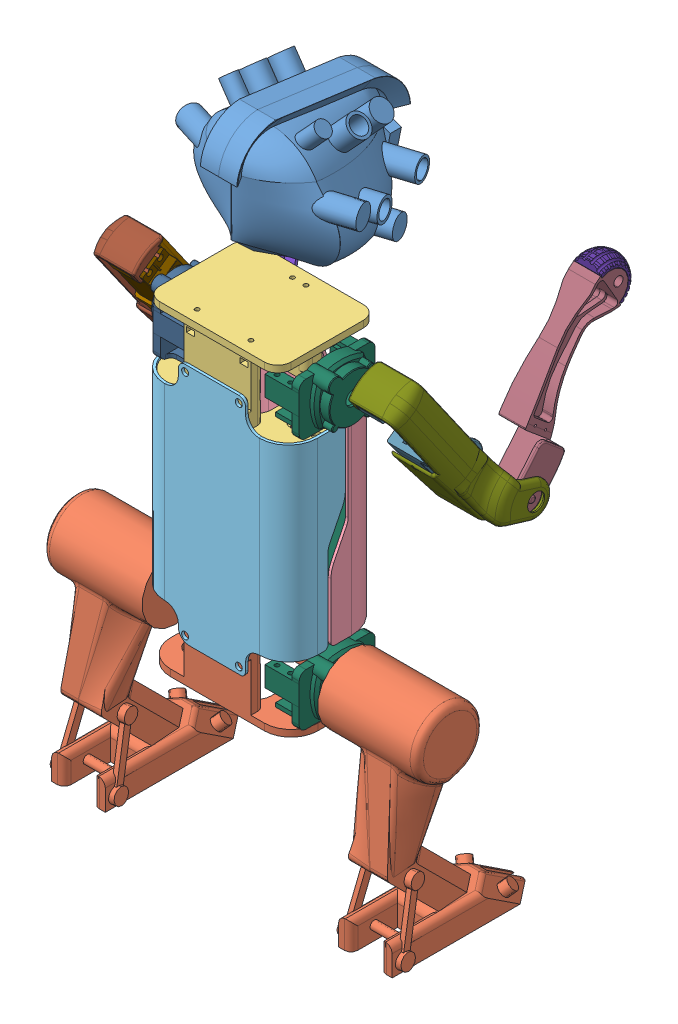
SolidWorks assembly SpotMicroAI, configuration 00. Lengths in mm.
Overall size (344.81 486.01 235.57).
36 component instances, 24 part files, 20 mates.
Components (placement in the parent):
- Rear_Shoulder-1: Rear_Shoulder [Default] at origin size (110 57.5 70)
  - Rear_Inner_Shoulder-1: Rear_Inner_Shoulder [Default] at (267.0968 85.9341 878.7869) x (-1 0 0) z (0 0 -1) size (110 5.15 70)
  - Rear_Outer_Shoulder-1: Rear_Outer_Shoulder [Default] at (267.0969 90.6943 -58.2152) x (-1 0 0) z (0 0 1) size (110 52.53 70)
- Front Shoulder-1: Front Shoulder [Default] at origin size (110 52.5 70)
  - Front_Inner_Shoulder-1: Front_Inner_Shoulder [Default] at (115.6208 217.934 444.7666) x (-1 0 0) z (0 1 0) size (110 70 52.5)
- Covers-1: Covers [Default] at origin size (115.6 323.29 74)
  - Cover_Nose-1: Cover_Nose [Default] at (291.792 648.6711 914.4489) x (0 1 0) z (0 0 -1) size (93.46 115.6 70.05) (hidden)
  - Cover_Bottom-1: Cover_Bottom [Default] at (1154.1394 1170.0941 1665.8069) x (0 -1 0) z (-1 0 0) size (180 42.4 114)
  - Cover_Top-1: Cover_Top [Default] at (1154.1394 -861.2249 -846.2737) x (0 1 0) z (-1 0 0) size (180 42.5 114.01)
  - Cover_Rear_Plain-1: Cover_Rear_Plain [Default] at (398.4845 261.595 791.8833) x (0 0 -1) z (0 1 0) size (70.05 114.01 69.83) (hidden)
- Chassis-1: Chassis [Default] at origin size (110 127 29)
  - Chassis_Right_Side-1: Chassis_Right_Side [Default] at (205.6209 154.434 412.2666) x (0 0 1) z (-1 0 0) size (29 127 6.5)
  - Chassis_Left_Side-1: Chassis_Left_Side [Default] at (95.6208 154.4341 412.2666) x (0 0 1) z (1 0 0) size (29 127 6.5)
- Left Arm-1: Left Arm [Default] at (15.3219 0 395.1883) x (0 1 0) z (0.258819 0 -0.965926) size (144.09 143.1 205.53)
  - Left_Wrist-1: Left_Wrist [Default] at (208.18 556.7001 -69.0557) x (0.766044 -0.166366 0.620885) z (-0.642788 -0.198267 0.739942) size (150.01 36.9 30.01)
  - Left_MidLimb-1: Left_MidLimb [Default] at (818.6858 196.1975 -412.3318) x (-0.573576 0.212012 -0.79124) z (-0.819152 -0.148453 0.554032) size (40.2 40.42 137.43)
  - Left_Hind_Limb-1: Left_Hind_Limb [Default] at (269.686 62.3829 30.3404) x (0 -0.965926 -0.258819) z (0 0.258819 -0.965926) size (37.51 46 56.55)
  - Left_MidLimb_Cover-1: Left_MidLimb_Cover [Default] at (1075.7599 185.3339 -217.1444) x (-0.573576 0.212012 -0.79124) z (-0.819152 -0.148453 0.554032) size (43.12 46.4 143.61)
  - Foot-1: Foot [Default] at (334.478 189.9471 78.7023) x (0.864275 0.130191 -0.48588) z (-0.50302 0.223691 -0.834825) size (39.57 20.99 19.53)
- Left Arm_1-1: Left Arm_1 [Default] at (15.3219 -285 395.1883) x (0 1 0) z (0.258819 0 -0.965926) size (46 50.87 64.33)
  - Left_Hind_Limb-1: Left_Hind_Limb [Default] at (367.1861 62.3831 30.3403) x (0 -0.965926 -0.258819) z (0 0.258819 -0.965926) size (37.51 46 56.55) (hidden)
- Right Arm(Mirror)-1: Right Arm(Mirror) [Default] at (285.9198 0 395.1883) x (0 1 0) z (0.258819 0 0.965926) size (144.09 143.1 205.53)
  - Right_Wrist-1: Right_Wrist [Default] at (208.18 556.7001 69.0557) x (0.766044 -0.166366 -0.620885) z (0.642788 0.198267 0.739942) size (150.01 36.9 30.01)
  - Right_MidLimb-1: Right_MidLimb [Default] at (818.6858 196.1975 412.3318) x (-0.573576 0.212012 0.79124) z (0.819152 0.148453 0.554032) size (40.2 40.42 137.43)
  - Right_Hind_Limb-1: Right_Hind_Limb [Default] at (269.686 62.3829 -30.3404) x (0 -0.965926 0.258819) z (0 -0.258819 -0.965926) size (37.61 46 56.55)
  - Right_MidLimb_Cover-1: Right_MidLimb_Cover [Default] at (1075.7599 185.3339 217.1444) x (-0.573576 0.212012 0.79124) z (0.819152 0.148453 0.554032) size (43.12 46.48 143.61)
  - Foot(Mirror)-1: Foot(Mirror) [Default] at (334.478 189.9471 -78.7023) x (0.864275 0.130191 0.48588) z (0.50302 -0.223691 -0.834825) size (39.57 20.99 19.53)
- Right Arm(Mirror)_1-1: Right Arm(Mirror)_1 [Default] at (285.9198 -285 395.1883) x (0 1 0) z (0.258819 0 0.965926) size (46 50.96 64.36)
  - Right_Hind_Limb-1: Right_Hind_Limb [Default] at (367.1861 62.3831 -30.3403) x (0 -0.965926 0.258819) z (0 -0.258819 -0.965926) size (37.61 46 56.55)
- Servo Motor MG996R  With Attachments-2: Servo Motor MG996R  With Attachments [По умолчанию] at (64.3664 178.4471 324.2238) x (0 -0.76661 0.642114) z (0 0.642114 0.76661) size (56.95 44.55 19.7)
- Servo Motor MG996R  With Attachments-4: Servo Motor MG996R  With Attachments [По умолчанию] at (71.1148 242.1871 397.9446) x (0 0.819152 0.573576) z (0 0.573576 -0.819152) size (56.95 44.55 19.7)
- Голова-1: Голова [По умолчанию] at (150.6209 312.2493 326.128) size (134.3 100.82 129.63)
- Бёдрышко-1: Бёдрышко [Правая] at (257.4935 -81.8487 439.3311) x (0 0 1) z (0 -1 0) size (113.52 74 166.38)
- Бёдрышко-5: Бёдрышко [Левая] at (126.7482 -81.8487 439.3311) x (0 0 1) z (0 -1 0) size (113.52 74 166.38)
- Деталь2^SpotMicroAI-1: Деталь2^SpotMicroAI [По умолчанию] at origin (virtual)
- Верхушка-Власти-1: Верхушка-Власти [По умолчанию] at (150.6209 275.434 409.7667) x (1 0 0) z (0 -1 0) size (98 74 5)
Mates (geometry in assembly coordinates):
- Совпадение3: coincident anti-aligned: plane of Left Arm-1/Left_Wrist-1 through (64.3664 259.7717 255.9142) normal (1 0 0); plane of Servo Motor MG996R  With Attachments-2 through (64.3664 194.7722 302.0383) normal (-1 0 0)
- Концентричный14: concentric aligned: circle of Left Arm-1/Left_Wrist-1; cylinder of Servo Motor MG996R  With Attachments-2 through (66.7664 200.5533 312.1319) axis (-1 0 0) radius 2.1
- Параллельность4: parallel aligned: cylinder of Left Arm-1/Left_Wrist-1 through (64.3664 194.125 304.4711) axis (-1 0 0) radius 1.5; cylinder of Servo Motor MG996R  With Attachments-2 through (66.7664 194.2285 304.5808) axis (-1 0 0) radius 2.1
- Совпадение5: coincident anti-aligned: plane of Left Arm-1/Left_MidLimb-1 through (71.1148 192.4364 373.9508) normal (1 0 0); plane of Servo Motor MG996R  With Attachments-4 through (71.1148 216.5235 387.9404) normal (-1 0 0)
- Концентричный16: concentric aligned: cylinder of Left Arm-1/Left_MidLimb_Cover-1 through (70.9148 259.6044 416.1527) axis (-1 0 0) radius 2.0995; cylinder of Servo Motor MG996R  With Attachments-4 through (73.5148 259.6044 416.1527) axis (-1 0 0) radius 2.1
- Параллельность7: parallel: line of Left Arm-1/Left_MidLimb-1 through (71.1148 272.6314 404.522) axis (0 -0.819152 -0.573576); plane of Servo Motor MG996R  With Attachments-4 through (73.5148 225.7197 374.3894) normal (0 0.573576 -0.819152)
- Совпадение9: coincident anti-aligned: plane of Covers-1/Cover_Top-1 through (115.1208 224.434 446.7666) normal (0 0 1); plane of koltuk-2 through (154.166 214.1134 446.7666) normal (0 0 -1)
- Параллельность8: parallel anti-aligned: line of Covers-1/Cover_Nose-1 through (185.6209 278.8949 444.7666) axis (-1 0 0); line of koltuk-2 through (122.0356 220.6675 462.9431) axis (1 0 0)
- Совпадение10: coincident: point of Covers-1/Cover_Nose-1; unknown of Голова-1
- Параллельность9: parallel anti-aligned: plane of Covers-1/Cover_Bottom-1 through (207.6208 84.4352 399.7666) normal (1 0 0); plane of Бёдрышко-1 through (215.9935 59.6732 408.6366) normal (-1 0 0)
- Параллельность10: parallel aligned: plane of Rear_Shoulder-1/Rear_Outer_Shoulder-1 through (111.6209 33.4341 418.7665) normal (0 -1 0); plane of Бёдрышко-1 through (277.4935 -81.8487 439.3311) normal (0 -1 0)
- Параллельность13: parallel anti-aligned: plane of Covers-1/Cover_Top-1 through (93.6208 224.434 404.2666) normal (-1 0 0); plane of Бёдрышко-2 through (130.25 0.5275 310.0801) normal (1 0 0)
- Параллельность14: parallel aligned: plane of Rear_Shoulder-1/Rear_Outer_Shoulder-1 through (111.6209 33.4341 418.7665) normal (0 -1 0); plane of Бёдрышко-2 through (68.75 -140.9945 279.3855) normal (0 -1 0)
- Параллельность15: parallel anti-aligned: plane of Covers-1/Cover_Top-1 through (93.6208 224.434 404.2666) normal (-1 0 0); plane of Бёдрышко-5 through (85.2482 59.6732 408.6366) normal (1 0 0)
- Параллельность16: parallel aligned: plane of Rear_Shoulder-1/Rear_Outer_Shoulder-1 through (111.6209 33.4341 418.7665) normal (0 -1 0); plane of Бёдрышко-5 through (23.7482 -81.8487 439.3311) normal (0 -1 0)
- Концентричный17: concentric anti-aligned: cylinder of Бёдрышко-1 through (289.9935 59.6732 408.6366) axis (-1 0 0) radius 24.8578; cylinder of Бёдрышко-5 through (11.2482 59.6732 408.6366) axis (1 0 0) radius 24.8578
- Симметричный1: symmetric aligned: plane of Бёдрышко-1 through (215.9935 59.6732 408.6366) normal (-1 0 0); plane of Бёдрышко-5 through (85.2482 59.6732 408.6366) normal (1 0 0)
- Совпадение24: coincident anti-aligned: plane of Front Shoulder-1/Front_Inner_Shoulder-1 through (150.6208 270.434 380.7666) normal (0 1 0); plane of Верхушка-Власти-1 through (111.6209 270.434 382.7667) normal (0 -1 0)
- Концентричный18: concentric aligned: cylinder of Front Shoulder-1/Front_Inner_Shoulder-1 through (130.6209 270.434 437.7666) axis (0 -1 0) radius 1.6001; cylinder of Верхушка-Власти-1 through (130.6209 275.434 437.7667) axis (0 -1 0) radius 1.6
- Концентричный19: concentric aligned: cylinder of Front Shoulder-1/Front_Inner_Shoulder-1 through (145.6209 270.434 381.7667) axis (0 -1 0) radius 1.5999; cylinder of Верхушка-Власти-1 through (145.6209 275.434 381.7667) axis (0 -1 0) radius 1.6
